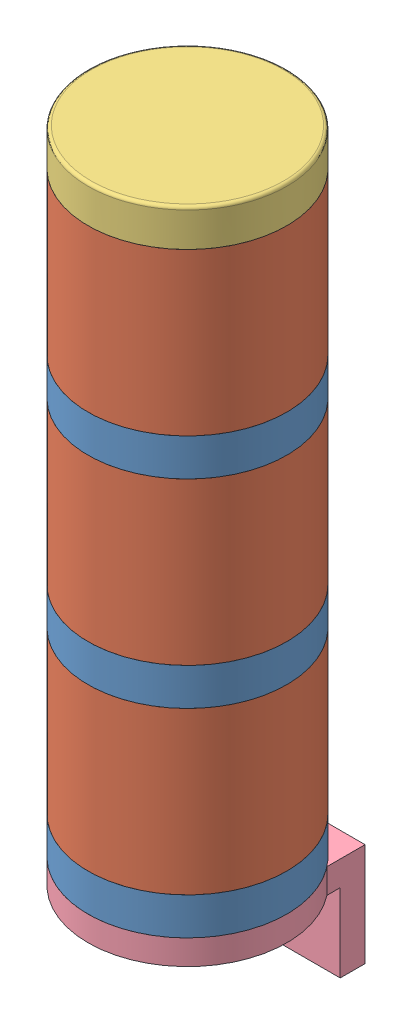
SolidWorks assembly Light Stack, configuration Default. Lengths in mm.
Overall size (50.8 188.27 50.8).
8 component instances, 4 part files, 8 mates.
Components (placement in the parent):
- Light Stack Seperator-1: Light Stack Seperator [Default] at origin size (50.8 15.88 50.8)
- Light Stack Diffuser-1: Light Stack Diffuser [Default] at (0 28.575 0) size (50.8 47.62 50.8)
- Light Stack Diffuser-2: Light Stack Diffuser [Default] at (0 79.375 0) size (50.8 47.62 50.8)
- Light Stack Seperator-2: Light Stack Seperator [Default] at (0 50.8 0) size (50.8 15.88 50.8)
- Light Stack Seperator-3: Light Stack Seperator [Default] at (0 101.6 0) size (50.8 15.88 50.8)
- Light Stack Diffuser-3: Light Stack Diffuser [Default] at (0 130.175 0) size (50.8 47.62 50.8)
- Light Stack Cap-1: Light Stack Cap [Default] at (0 152.4 0) size (50.8 9.53 50.8)
- Light Stack Base-1: Light Stack Base [Default] at (0 -7.9375 0) size (50.8 32.7 50.8)
Mates (geometry in assembly coordinates):
- Concentric1: concentric aligned: cylinder of Light Stack Seperator-1 through (0 -32.3252 0) axis (0 -1 0) radius 25.4; cylinder of Light Stack Diffuser-1 through (0 -3.7502 0) axis (0 -1 0) radius 25.4
- Coincident1: coincident anti-aligned: plane of Light Stack Seperator-1 through (0 4.7625 -22.225) normal (0 1 0); plane of Light Stack Diffuser-1 through (0 4.7625 -25.4) normal (0 -1 0)
- Parallel1: parallel aligned: plane of Light Stack Diffuser-1 through (3.175 -14.876 0) normal (1 0 0)
- Coincident3: coincident anti-aligned: plane of Light Stack Diffuser-3 through (0 147.6375 -22.225) normal (0 1 0); plane of Light Stack Cap-1 through (0 147.6375 -25.4) normal (0 -1 0)
- Concentric2: concentric aligned: cylinder of Light Stack Diffuser-3 through (0 97.8498 0) axis (0 -1 0) radius 25.4; cylinder of Light Stack Cap-1 through (0 120.0748 0) axis (0 -1 0) radius 25.4
- Concentric3: concentric aligned: cylinder of Light Stack Seperator-1 through (0 -32.3252 0) axis (0 -1 0) radius 25.4; cylinder of Light Stack Base-1 through (0 -40.2627 0) axis (0 -1 0) radius 22.225
- Coincident4: coincident anti-aligned: plane of Light Stack Seperator-1 through (0 -4.7625 -25.4) normal (0 -1 0); plane of Light Stack Base-1 through (0 -4.7625 -22.225) normal (0 1 0)
- Parallel2: parallel aligned: plane of Light Stack Base-1 through (20 -7.9375 0) normal (1 0 0)
